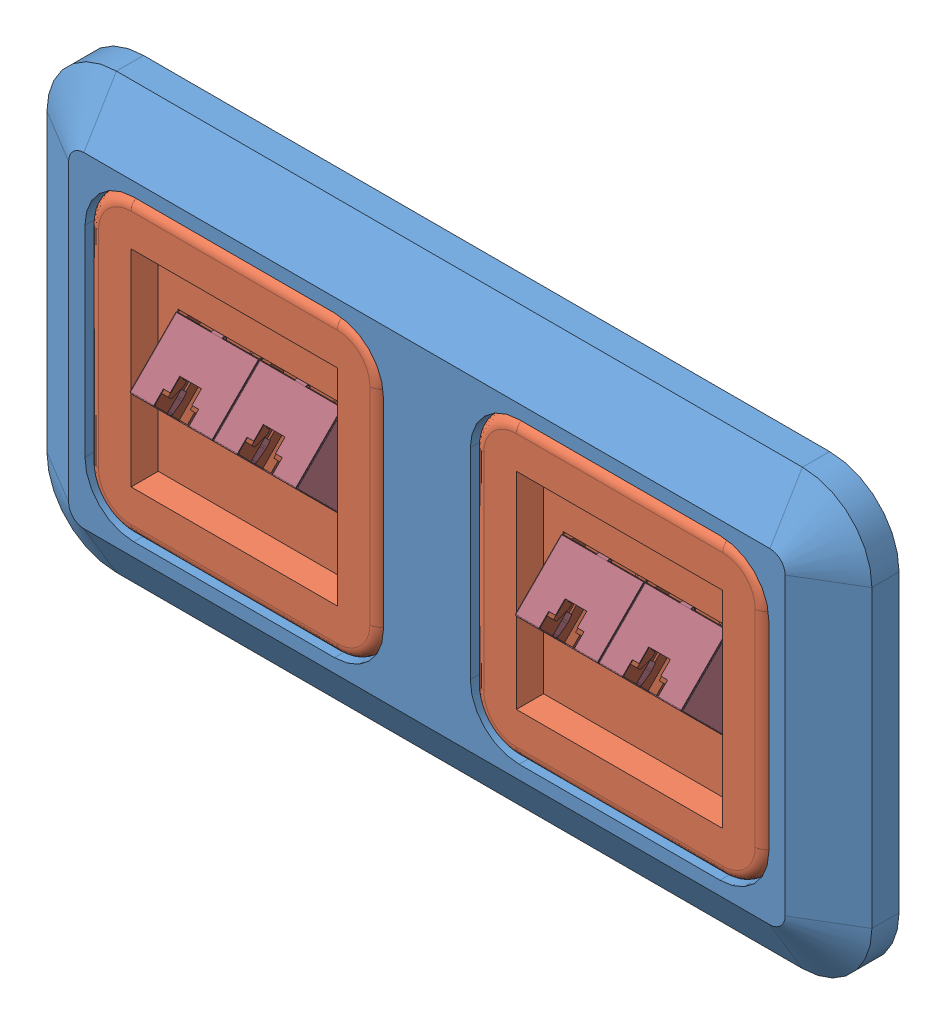
SolidWorks assembly Steckdose_2er-RJ45, configuration Standard. Lengths in mm.
Overall size (152 80 25.23).
53 component instances, 13 part files, 6 mates.
Components (placement in the parent):
- Wandplatte-1: Wandplatte [2er] at (17.3004 67.6649 10.1448) size (152 80 11)
- Steckdose-RJ45-1: Steckdose-RJ45 [Standard] at (177.7047 18.6812 -53.8826) x (0 -1 0) z (0 0 1) size (54 54 25.23)
  - Buchse-RJ45-1: Buchse-RJ45 [Standard] at (-88.9836 -48.9043 64.0274) size (54 54 6.5)
  - 65864-1: 65864 [Default] at (-88.8386 -41.2043 53.1274) size (17.49 15.42 25.23)
    - 65864_01-1: 65864_01 [Default] at origin size (9.69 0.75 13.83)
    - 65864_02-1: 65864_02 [Default] at origin size (9.44 0.68 13.83)
    - 65864_03-1: 65864_03 [Default] at origin size (9.69 0.61 13.84)
    - 65864_04-1: 65864_04 [Default] at origin size (9.44 0.54 13.83)
    - 65864_05-1: 65864_05 [Default] at origin size (9.69 0.54 13.82)
    - 65864_06-1: 65864_06 [Default] at origin size (9.44 0.6 13.83)
    - 65864_07-1: 65864_07 [Default] at origin size (9.69 0.68 13.83)
    - 65864_08-1: 65864_08 [Default] at origin size (9.44 0.75 13.83)
    - 65864_09-1: 65864_09 [Default] at origin size (17.11 15.1 23.65)
    - 65864_10-1: 65864_10 [Default] at origin size (6.36 10.31 6.36)
    - 65864_11-1: 65864_11 [Default] at origin size (17.49 15.42 25.23)
  - 65864-2: 65864 [Default] at (-88.8386 -56.6043 53.1274) size (17.49 15.42 25.23)
    - 65864_01-1: 65864_01 [Default] at origin size (9.69 0.75 13.83)
    - 65864_02-1: 65864_02 [Default] at origin size (9.44 0.68 13.83)
    - 65864_03-1: 65864_03 [Default] at origin size (9.69 0.61 13.84)
    - 65864_04-1: 65864_04 [Default] at origin size (9.44 0.54 13.83)
    - 65864_05-1: 65864_05 [Default] at origin size (9.69 0.54 13.82)
    - 65864_06-1: 65864_06 [Default] at origin size (9.44 0.6 13.83)
    - 65864_07-1: 65864_07 [Default] at origin size (9.69 0.68 13.83)
    - 65864_08-1: 65864_08 [Default] at origin size (9.44 0.75 13.83)
    - 65864_09-1: 65864_09 [Default] at origin size (17.11 15.1 23.65)
    - 65864_10-1: 65864_10 [Default] at origin size (6.36 10.31 6.36)
    - 65864_11-1: 65864_11 [Default] at origin size (17.49 15.42 25.23)
- Steckdose-RJ45-2: Steckdose-RJ45 [Standard] at (106.7047 18.6812 -53.8826) x (0 -1 0) z (0 0 1) size (54 54 25.23)
  - Buchse-RJ45-1: Buchse-RJ45 [Standard] at (-88.9836 -48.9043 64.0274) size (54 54 6.5)
  - 65864-1: 65864 [Default] at (-88.8386 -41.2043 53.1274) size (17.49 15.42 25.23)
    - 65864_01-1: 65864_01 [Default] at origin size (9.69 0.75 13.83)
    - 65864_02-1: 65864_02 [Default] at origin size (9.44 0.68 13.83)
    - 65864_03-1: 65864_03 [Default] at origin size (9.69 0.61 13.84)
    - 65864_04-1: 65864_04 [Default] at origin size (9.44 0.54 13.83)
    - 65864_05-1: 65864_05 [Default] at origin size (9.69 0.54 13.82)
    - 65864_06-1: 65864_06 [Default] at origin size (9.44 0.6 13.83)
    - 65864_07-1: 65864_07 [Default] at origin size (9.69 0.68 13.83)
    - 65864_08-1: 65864_08 [Default] at origin size (9.44 0.75 13.83)
    - 65864_09-1: 65864_09 [Default] at origin size (17.11 15.1 23.65)
    - 65864_10-1: 65864_10 [Default] at origin size (6.36 10.31 6.36)
    - 65864_11-1: 65864_11 [Default] at origin size (17.49 15.42 25.23)
  - 65864-2: 65864 [Default] at (-88.8386 -56.6043 53.1274) size (17.49 15.42 25.23)
    - 65864_01-1: 65864_01 [Default] at origin size (9.69 0.75 13.83)
    - 65864_02-1: 65864_02 [Default] at origin size (9.44 0.68 13.83)
    - 65864_03-1: 65864_03 [Default] at origin size (9.69 0.61 13.84)
    - 65864_04-1: 65864_04 [Default] at origin size (9.44 0.54 13.83)
    - 65864_05-1: 65864_05 [Default] at origin size (9.69 0.54 13.82)
    - 65864_06-1: 65864_06 [Default] at origin size (9.44 0.6 13.83)
    - 65864_07-1: 65864_07 [Default] at origin size (9.69 0.68 13.83)
    - 65864_08-1: 65864_08 [Default] at origin size (9.44 0.75 13.83)
    - 65864_09-1: 65864_09 [Default] at origin size (17.11 15.1 23.65)
    - 65864_10-1: 65864_10 [Default] at origin size (6.36 10.31 6.36)
    - 65864_11-1: 65864_11 [Default] at origin size (17.49 15.42 25.23)
Mates (geometry in assembly coordinates):
- Deckungsgleich1: coincident: plane of Wandplatte-1 through (110.3004 89.1649 4.1448) normal (0 0 1); plane of Steckdose-RJ45-1/Buchse-RJ45-1 through (109.8004 126.6649 4.1448) normal (0 0 -1)
- Deckungsgleich2: coincident: plane of Wandplatte-1 through (39.3004 89.1649 4.1448) normal (0 0 1); plane of Steckdose-RJ45-2/Buchse-RJ45-1 through (38.8004 126.6649 4.1448) normal (0 0 -1)
- Abstand1: distance = 0.5 mm: plane of Steckdose-RJ45-2/Buchse-RJ45-1 through (76.8004 80.6649 4.1448) normal (0 -1 0); plane of Wandplatte-1 through (39.3004 80.1649 4.1448) normal (0 1 0)
- Abstand2: distance = 0.5 mm: plane of Steckdose-RJ45-1/Buchse-RJ45-1 through (147.8004 80.6649 4.1448) normal (0 -1 0); plane of Wandplatte-1 through (110.3004 80.1649 4.1448) normal (0 1 0)
- Abstand3: distance = 0.5 mm anti-aligned: plane of Wandplatte-1 through (156.3004 126.1649 4.1448) normal (-1 0 0); plane of Steckdose-RJ45-1/Buchse-RJ45-1 through (155.8004 126.6649 4.1448) normal (1 0 0)
- Abstand4: distance = 0.5 mm anti-aligned: plane of Steckdose-RJ45-2/Buchse-RJ45-1 through (84.8004 126.6649 4.1448) normal (1 0 0); plane of Wandplatte-1 through (85.3004 126.1649 4.1448) normal (-1 0 0)
